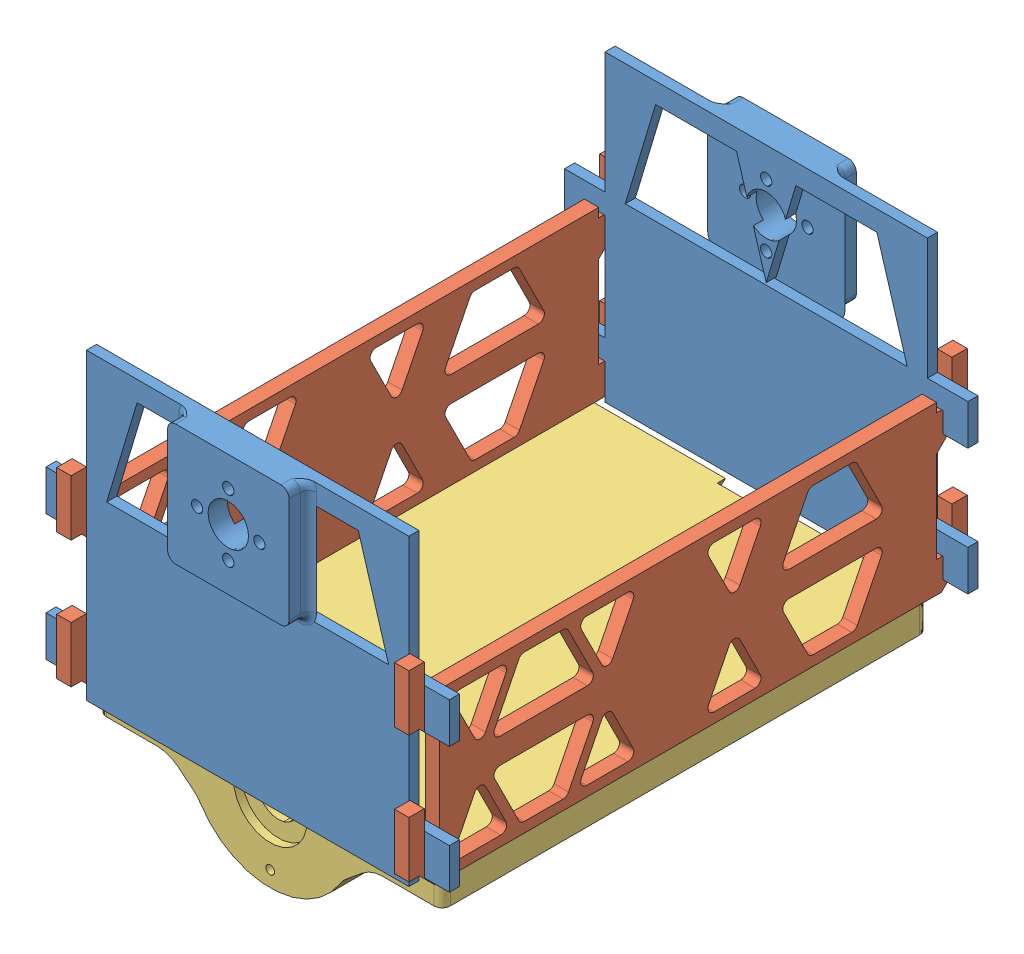
SolidWorks assembly newbatterybox, configuration Default. Lengths in mm.
Overall size (126.91 125.55 177.77).
5 component instances, 3 part files, 12 mates.
Components (placement in the parent):
- battery mount 2new-1: battery mount 2new [Default] at (94.7368 148.2987 104.3034) size (126.59 95.22 9.26)
- battery holder doornew-1: battery holder doornew [Default] at (130.7921 88.4792 193.1907) x (0 0 1) z (-1 0 0) size (175.26 62.23 4.51)
- battery holder doornew-2: battery holder doornew [Default] at (24.7725 88.4792 193.1907) x (0 0 1) z (-1 0 0) size (175.26 62.23 4.51)
- battery mount 2new-3: battery mount 2new [Default] at (56.3193 148.2987 282.078) x (-1 0 0) z (0 0 -1) size (126.59 95.22 9.26)
- battery mount wide-1: battery mount wide [Default] at (20.264 53.0741 115.3867) x (0 0 -1) z (1 0 0) size (152.4 30.33 107.95)
Mates (geometry in assembly coordinates):
- Coincident7: coincident anti-aligned: plane of battery mount 2new-1 through (126.2836 148.2987 110.3867) normal (1 0 0); plane of battery holder doornew-1 through (126.2836 88.4792 193.1907) normal (-1 0 0)
- Coincident8: coincident anti-aligned: plane of battery mount 2new-1 through (126.2836 103.8487 113.5617) normal (0 -1 0); plane of battery holder doornew-1 through (130.7921 103.8487 115.2127) normal (0 1 0)
- Coincident9: coincident anti-aligned: plane of battery mount 2new-1 through (25.09 103.8487 113.5617) normal (0 -1 0); plane of battery holder doornew-2 through (24.7725 103.8487 115.2127) normal (0 1 0)
- Coincident10: coincident anti-aligned: plane of battery mount 2new-1 through (20.264 97.4987 113.5617) normal (1 0 0); plane of battery holder doornew-2 through (20.264 88.4792 193.1907) normal (-1 0 0)
- Coincident11: coincident anti-aligned: plane of battery mount 2new-1 through (94.7368 148.2987 110.3867) normal (0 0 -1); plane of battery holder doornew-2 through (24.7725 103.8487 110.3867) normal (0 0 1)
- Coincident12: coincident anti-aligned: plane of battery holder doornew-2 through (24.7725 103.8487 271.1687) normal (0 1 0); plane of battery mount 2new-3 through (24.7725 103.8487 272.8197) normal (0 -1 0)
- Coincident13: coincident anti-aligned: plane of battery holder doornew-2 through (24.7725 103.8487 275.9947) normal (0 0 -1); plane of battery mount 2new-3 through (56.3193 148.2987 275.9947) normal (0 0 1)
- Coincident14: coincident anti-aligned: plane of battery holder doornew-2 through (24.7725 88.4792 193.1907) normal (1 0 0); plane of battery mount 2new-3 through (24.7725 148.2987 275.9947) normal (-1 0 0)
- Coincident15: coincident anti-aligned: plane of battery mount 2new-3 through (94.4193 53.0741 275.9947) normal (0 -1 0); plane of battery mount wide-1 through (128.214 53.0741 110.3867) normal (0 1 0)
- Coincident16: coincident anti-aligned: plane of battery mount 2new-1 through (94.7368 148.2987 110.3867) normal (0 0 -1); plane of battery holder doornew-1 through (130.7921 103.8487 110.3867) normal (0 0 1)
- Distance1: distance = 5 mm aligned: plane of battery mount 2new-1 through (94.7368 148.2987 110.3867) normal (0 0 -1); plane of battery mount wide-1 through (128.214 53.0741 115.3867) normal (0 0 -1)
- Coincident18: coincident aligned: plane of battery holder doornew-2 through (20.264 88.4792 193.1907) normal (-1 0 0); plane of battery mount wide-1 through (20.264 53.0741 110.3867) normal (-1 0 0)
